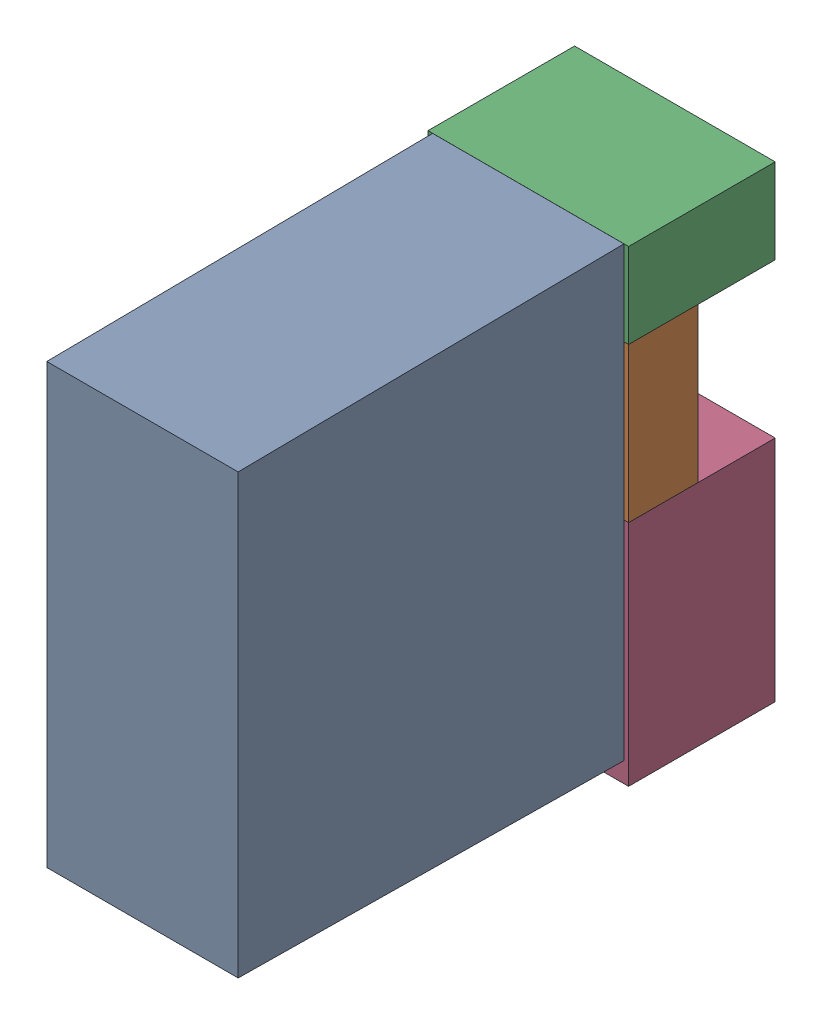
SolidWorks assembly K17, configuration Default. Lengths in mm.
Overall size (13 30.3 34.5).
7 component instances, 4 part files, 0 mates.
Components (placement in the parent):
- relais_40_61_8_006_0000-1: relais_40_61_8_006_0000 [Default] at (260.985 15.7216 9.5) x (0 1 0) z (1 0 0) size (29 30 12.4)
- 1151725064-1: 1151725064 [Default] at (260.985 34.225 5) size (13 10 4.5)
  - Extruded_3-1: Extruded_3 [Default] at origin size (13 10 4.5)
- 1151724928-1: 1151724928 [Default] at (260.985 41.975 0) size (13 5.5 9.5)
  - Extruded_2-1: Extruded_2 [Default] at origin size (13 5.5 9.5)
- 1151724792-1: 1151724792 [Default] at (260.985 21.825 0) size (13 14.8 9.5)
  - Extruded_4-1: Extruded_4 [Default] at origin size (13 14.8 9.5)
